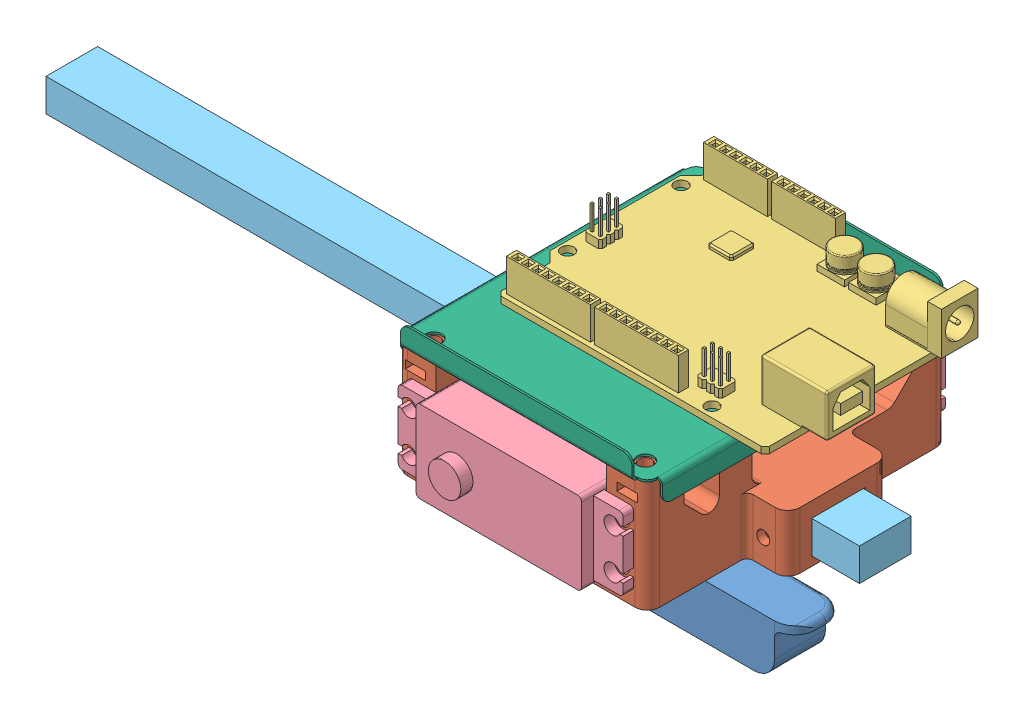
SolidWorks assembly Main Assembly, configuration Default. Lengths in mm.
Overall size (200.55 54.21 91).
7 component instances, 6 part files, 23 mates.
Components (placement in the parent):
- Battery Holder-1: Battery Holder [Default] at (44.3 -8.8 19.75) x (-1 0 0) z (0 0 1) size (98.1 13.11 45.5)
- Chassis-1: Chassis [Default] at origin size (82 27.5 74)
- Arduino UNO-1: Arduino UNO [Default] at (6.8 29 -8.85) x (-1 0 0) z (0 0 -1) size (74.8 12.1 53.3)
- Motor-1: Motor [Default] at (-1 12.25 -42.5) size (55.3 20.2 37.5)
- Motor-2: Motor [Default] at (-1 12.25 42.5) x (1 0 0) z (0 0 -1) size (55.3 20.2 37.5)
- Balsa Shaft-1: Balsa Shaft [Default] at (-148.4953 6 0) size (200 8 12.7)
- Shield Plate-1: Shield Plate [Default] at (-1 28 0) size (64.47 10.5 76.47)
Mates (geometry in assembly coordinates):
- Coincident2: coincident aligned: plane of Chassis-1 through (0 0 0) normal (0 0 1); plane of assembly through (0 0 0) normal (0 0 1)
- Coincident3: coincident aligned: plane of Chassis-1 through (0 0 0) normal (0 1 0); plane of assembly through (0 0 0) normal (0 1 0)
- Coincident4: coincident aligned: plane of Chassis-1 through (0 0 0) normal (1 0 0); plane of assembly through (0 0 0) normal (1 0 0)
- Coincident5: coincident anti-aligned: plane of Battery Holder-1 through (44.3 0 19.75) normal (0 1 0); plane of Chassis-1 through (0 0 0) normal (0 -1 0)
- Parallel1: parallel anti-aligned: plane of Battery Holder-1; plane of Chassis-1 through (0 0 0) normal (1 0 0)
- Coincident7: coincident aligned: plane of Battery Holder-1 through (44.3 -8.8 0) normal (0 0 1); plane of Chassis-1 through (0 0 0) normal (0 0 1)
- Parallel2: parallel anti-aligned: plane of Chassis-1 through (0 0 0) normal (1 0 0); plane of Arduino UNO-1 through (6.8 29 -8.85) normal (-1 0 0)
- Parallel3: parallel anti-aligned: plane of Chassis-1 through (0 0 0) normal (0 1 0); plane of Arduino UNO-1 through (-26.2 29 17.8) normal (0 -1 0)
- Concentric1: concentric aligned: circle of Battery Holder-1; circle of Chassis-1
- Concentric2: concentric aligned: circle of Chassis-1; circle of Arduino UNO-1
- Concentric3: concentric aligned: circle of Chassis-1; circle of Arduino UNO-1
- Concentric4: concentric anti-aligned: cylinder of Chassis-1 through (-26 17.25 -24) axis (0 0 -1) radius 1.55; cylinder of Motor-1 through (-26 17.25 -39.6) axis (0 0 1) radius 2.05
- Concentric5: concentric anti-aligned: cylinder of Chassis-1 through (-26 7.25 -24) axis (0 0 -1) radius 1.55; cylinder of Motor-1 through (-26 7.25 -39.6) axis (0 0 1) radius 2.05
- Coincident10: coincident anti-aligned: plane of Chassis-1 through (37.5 4 -37) normal (0 0 -1); plane of Motor-1 through (-26 7.25 -37) normal (0 0 1)
- Concentric6: concentric aligned: circle of Chassis-1; cylinder of Motor-2 through (-26 7.25 39.6) axis (0 0 -1) radius 2.05
- Concentric7: concentric aligned: circle of Chassis-1; cylinder of Motor-2 through (-26 17.25 39.6) axis (0 0 -1) radius 2.05
- Coincident11: coincident anti-aligned: plane of Chassis-1 through (37.5 4 37) normal (0 0 1); plane of Motor-2 through (-26 17.25 37) normal (0 0 -1)
- Coincident15: coincident anti-aligned: plane of Chassis-1 through (0 2 0) normal (0 1 0); plane of Balsa Shaft-1 through (51.5047 2 6.35) normal (0 -1 0)
- Coincident16: coincident aligned: plane of Chassis-1 through (0 0 0) normal (0 0 1); plane of Balsa Shaft-1 through (-148.4953 6 0) normal (0 0 1)
- Coincident17: coincident aligned: plane of Chassis-1 through (-1 0 0) normal (1 0 0); plane of Shield Plate-1 through (-1 28 0) normal (1 0 0)
- Coincident18: coincident aligned: plane of Shield Plate-1 through (-1 28 0) normal (0 0 1); plane of assembly through (0 0 0) normal (0 0 1)
- Coincident19: coincident anti-aligned: plane of Chassis-1 through (0 27.5 0) normal (0 1 0); plane of Shield Plate-1 through (-1 27.5 0) normal (0 -1 0)
- Distance1: distance = 1 mm anti-aligned: plane of Shield Plate-1 through (-1 28 0) normal (0 1 0); plane of Arduino UNO-1 through (-26.2 29 17.8) normal (0 -1 0)
